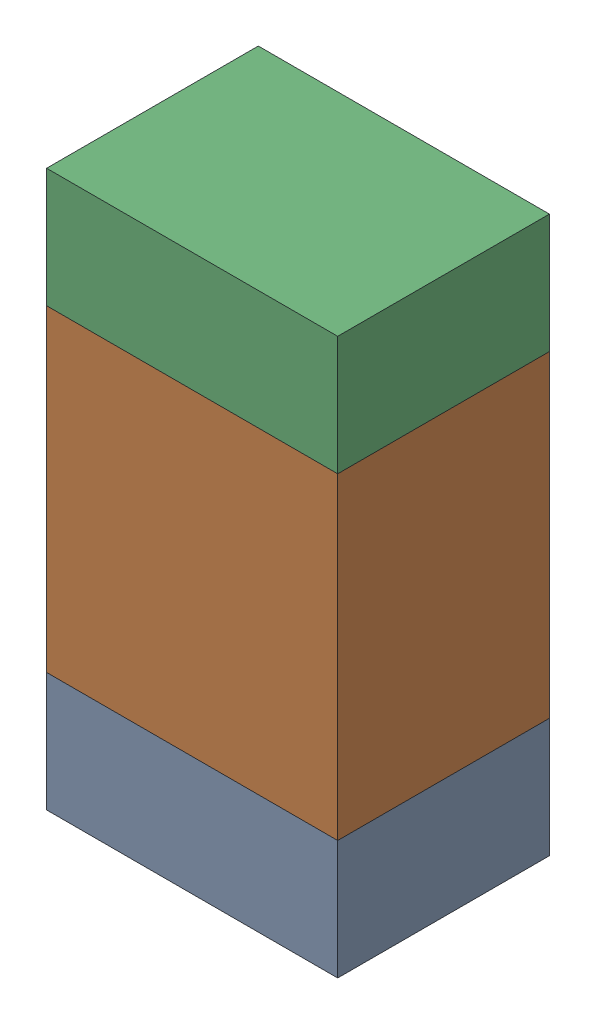
SolidWorks assembly R106_1PCB, configuration Default. Lengths in mm.
Overall size (0.55 1.05 0.4).
6 component instances, 2 part files, 0 mates.
Components (placement in the parent):
- 846483288-1: 846483288 [Default] at (117.5999 109.5876 0) size (0.55 0.22 0.4)
  - Extruded_12-1: Extruded_12 [Default] at origin size (0.55 0.22 0.4)
- 846483424-1: 846483424 [Default] at (117.5999 110.0001 0) size (0.55 0.6 0.4)
  - Extruded_13-1: Extruded_13 [Default] at origin size (0.55 0.6 0.4)
- 846483288-2: 846483288 [Default] at (117.5999 110.4126 0) size (0.55 0.22 0.4)
  - Extruded_12-1: Extruded_12 [Default] at origin size (0.55 0.22 0.4)
